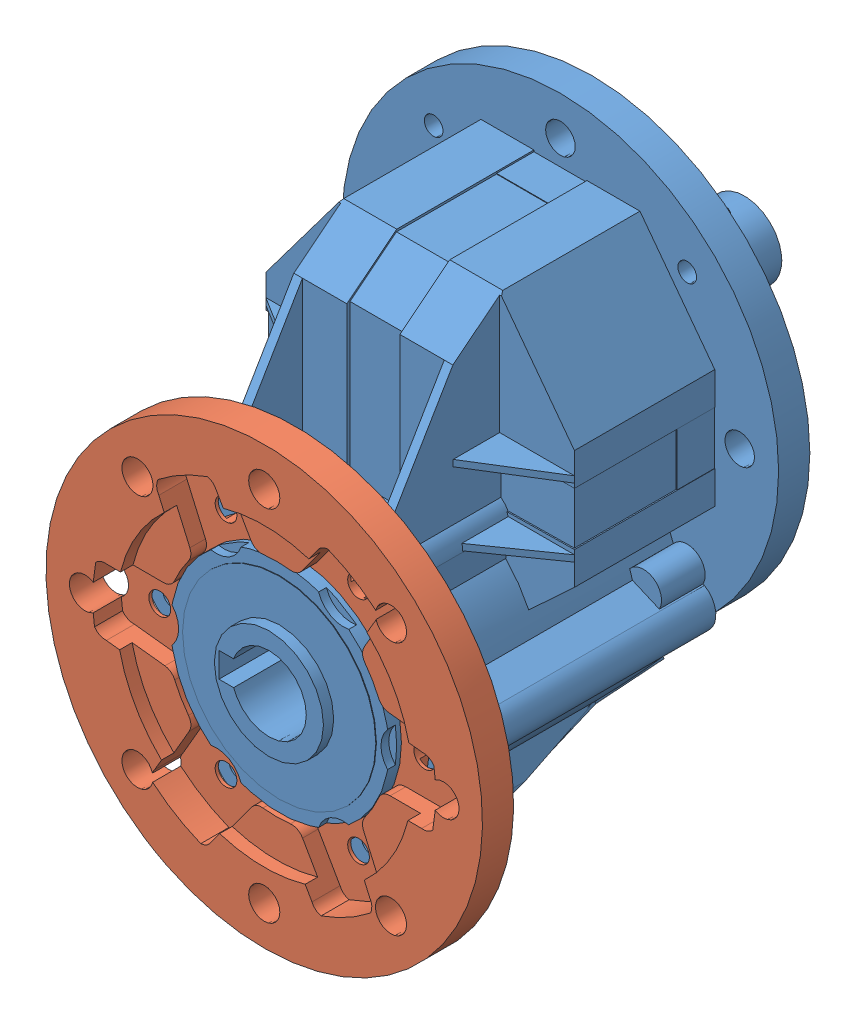
SolidWorks assembly Ensamblaje4, configuration Predeterminado. Lengths in mm.
Overall size (191.24 215.62 154).
2 component instances, 2 part files, 3 mates.
Components (placement in the parent):
- pm-80-1: pm-80 [Predeterminado] at (11.6216 30.962 -76.25) size (140 164.17 152.5)
- brida b5 pm-80 140-1: brida b5 pm-80 140 [Predeterminado] at (11.6216 -19.038 64.75) x (-0.5 -0.866025 0) z (0 0 1) size (140 140 13)
Mates (geometry in assembly coordinates):
- Concéntrica1: concentric: cylinder of pm-80-1 through (11.6216 -19.038 72.75) axis (0 0 -1) radius 35; circle of brida b5 pm-80 140-1
- Coincidente1: coincident: plane of pm-80-1 through (11.6216 -19.038 64.75) normal (0 0 1); plane of brida b5 pm-80 140-1 through (11.6216 -19.038 64.75) normal (0 0 -1)
- Concéntrica2: concentric anti-aligned: circle of pm-80-1; circle of brida b5 pm-80 140-1
